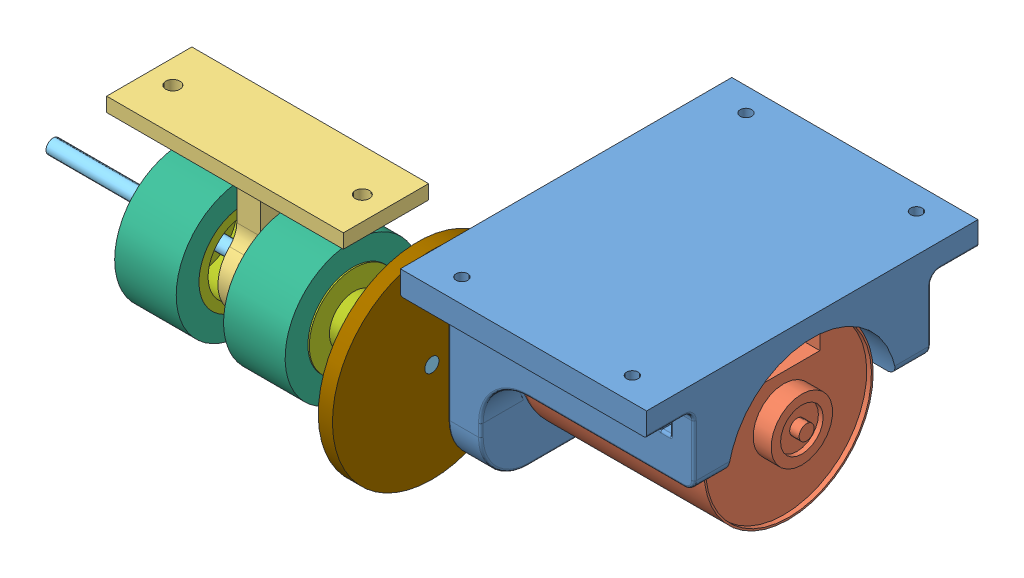
SolidWorks assembly SousAssemblageMoteurComplet, configuration Défaut. Lengths in mm.
Overall size (134.9 58.55 89.71).
14 component instances, 9 part files, 17 mates.
Components (placement in the parent):
- MoteurEtSupport-1: MoteurEtSupport [Défaut] at (175.3767 115.3051 355.1381) x (0 1 0) z (0 0 -1) size (42.55 57.9 70)
  - SupportMoteur-1: SupportMoteur [Défaut] at (-2.7774 -21.4781 70) size (42.55 52 70)
  - Moteur-1: Moteur [Défaut] at (-4.7774 18.5219 45) x (1 0 0) z (0 -1 0) size (35.75 35.75 56.7)
- piecemaintientchariot-1: piecemaintientchariot [Défaut] at (103.8575 100.6487 331.5754) size (50 31.79 18)
- RoulementàBilles-1: RoulementàBilles [Défaut] at (106.8021 108.7409 335.5754) size (4 10 10)
- Tige_entre_roues-1: Tige_entre_roues [Défaut] at (63.9986 108.7409 335.5754) size (80 3 3)
- RoueAssemblee-1: RoueAssemblee [Défaut] at (119.9243 114.0834 363.6739) x (-1 0 0) z (0 -0.197919 -0.980218) size (16.9 28.6 28.6)
  - Roue1-1: Roue1 [Défaut] at (-7.3778 0.3244 28.6) size (13 28.6 28.6)
  - Roue2-1: Roue2 [Défaut] at (-7.6778 0.3244 28.6) x (0 -1 0) z (0 0 1) size (19 16.9 19)
- RoueAssemblee-2: RoueAssemblee [Défaut] at (98.6799 108.2781 306.9773) x (1 0 0) z (0 0.004838 0.999988) size (16.9 28.6 28.6)
  - Roue1-1: Roue1 [Défaut] at (-7.3778 0.3244 28.6) size (13 28.6 28.6)
  - Roue2-1: Roue2 [Défaut] at (-7.6778 0.3244 28.6) x (0 -1 0) z (0 0 1) size (19 16.9 19)
- PEngrenage-1: PEngrenage [Défaut] at (140.9986 110.5276 310.1381) x (1 0 0) z (0 0.064382 0.997925) size (7.5 9 9)
- Gengrenage-1: Gengrenage [Défaut] at (143.9986 108.7409 335.5754) x (0 -0.815974 -0.578088) z (0 0.578088 -0.815974) size (42 8.4 42)
Mates (geometry in assembly coordinates):
- Coïncidente10: coincident: plane of PEngrenage-1 through (140.9986 110.5276 310.1381) normal (-1 0 0); plane of Gengrenage-1 through (140.9986 103.0291 331.5288) normal (-1 0 0)
- Tangent3: tangent: cylinder of PEngrenage-1 through (135.482 110.5276 310.1381) axis (-1 0 0) radius 4.5; cylinder of Gengrenage-1 through (143.9986 108.7409 335.5754) axis (1 0 0) radius 21
- Coaxiale12: concentric: circle of MoteurEtSupport-1/Moteur-1; cylinder of PEngrenage-1 through (140.9986 110.5276 310.1381) axis (1 0 0) radius 1.5
- Coïncidente11: coincident: plane of MoteurEtSupport-1/Moteur-1 through (140.9986 110.5276 310.1381) normal (-1 0 0); circle of PEngrenage-1
- Coaxiale13: concentric: circle of Tige_entre_roues-1; cylinder of Gengrenage-1 through (143.9986 108.7409 335.5754) axis (-1 0 0) radius 1.5
- Coïncidente12: coincident: circle of Tige_entre_roues-1; circle of Gengrenage-1
- Coaxiale14: concentric: cylinder of Tige_entre_roues-1 through (146.6619 108.7409 335.5754) axis (1 0 0) radius 1.5; circle of RoueAssemblee-1/Roue2-1
- Coaxiale15: concentric: circle of piecemaintientchariot-1; cylinder of RoulementàBilles-1 through (104.294 108.7409 335.5754) axis (-1 0 0) radius 5
- Coïncidente13: coincident: circle of piecemaintientchariot-1; circle of RoulementàBilles-1
- Coaxiale16: concentric: circle of RoulementàBilles-1; cylinder of Tige_entre_roues-1 through (146.6619 108.7409 335.5754) axis (1 0 0) radius 1.5
- Coaxiale17: concentric: cylinder of Tige_entre_roues-1 through (146.6619 108.7409 335.5754) axis (1 0 0) radius 1.5; circle of RoueAssemblee-2/Roue2-1
- Parallèle4: parallel: plane of MoteurEtSupport-1/SupportMoteur-1 through (198.8986 132.5276 285.1381) normal (0 1 0); plane of piecemaintientchariot-1 through (134.3021 132.5276 339.5754) normal (0 1 0)
- Coïncidente14: coincident: plane of MoteurEtSupport-1/SupportMoteur-1 through (198.8986 132.5276 285.1381) normal (0 1 0); plane of piecemaintientchariot-1 through (134.3021 132.5276 339.5754) normal (0 1 0)
- Parallèle5: parallel: plane of MoteurEtSupport-1/SupportMoteur-1 through (153.8986 112.5276 345.1381) normal (0 0 1); plane of assembly through (0 0 0) normal (0 0 1)
- Distance1: distance = 26 mm: cylinder of piecemaintientchariot-1 through (129.3021 100.7409 335.5754) axis (0 1 0) radius 1.5; cylinder of MoteurEtSupport-1/SupportMoteur-1 through (154.8986 137.5276 340.1381) axis (0 -1 0) radius 1.2295
- Distance2: distance = 15.5 mm: plane of RoueAssemblee-2/Roue1-1 through (91.3021 108.7409 335.5754) normal (-1 0 0); plane of piecemaintientchariot-1 through (106.8021 114.7409 339.5754) normal (-1 0 0)
- Distance3: distance = 15.5 mm: plane of piecemaintientchariot-1 through (111.8021 114.7365 339.5754) normal (1 0 0); plane of RoueAssemblee-1/Roue1-1 through (127.3021 108.7409 335.5754) normal (1 0 0)
